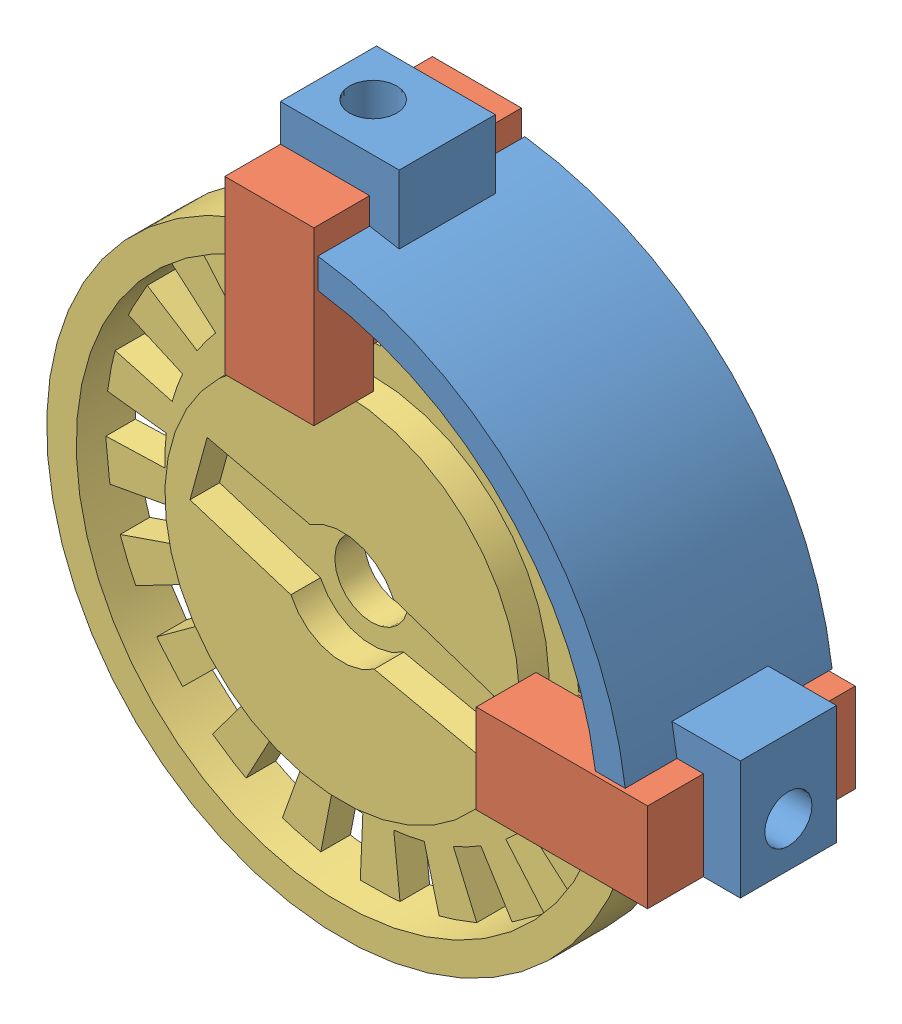
SolidWorks assembly wheel_w_encoder, configuration Default. Lengths in mm.
Overall size (52.67 52.67 14.28).
4 component instances, 3 part files, 9 mates.
Components (placement in the parent):
- encoders_holder2-1: encoders_holder2 [Default] at (1.6965 9.9141 32.1204) size (31.12 31.12 14)
- photo_interrupter-1: photo_interrupter [Default] at (4.7115 29.7141 39.3704) x (0 0 -1) z (-1 0 0) size (14.05 11.6 6.03)
- photo_interrupter-2: photo_interrupter [Default] at (21.4965 12.9291 39.3704) x (0 0 1) z (0 -1 0) size (14.05 11.6 6.03)
- wheel40-1: wheel40 [Default] at (1.6965 9.9141 37.4654) x (0.964469 -0.264196 0) z (0 0 1) size (40 40 4)
Mates (geometry in assembly coordinates):
- Concentric1: concentric: cylinder of encoders_holder2-1 through (1.6965 38.0141 39.3704) axis (0 1 0) radius 1.6; cylinder of photo_interrupter-1 through (1.6965 35.5141 39.3704) axis (0 1 0) radius 1.6
- Coincident1: coincident: plane of encoders_holder2-1 through (4.7215 35.5141 46.6204) normal (0 -1 0); plane of photo_interrupter-1 through (-1.3185 35.5141 46.3954) normal (0 1 0)
- Parallel1: parallel: plane of encoders_holder2-1 through (-1.3285 35.5141 46.6204) normal (-1 0 0); plane of photo_interrupter-1 through (-1.3185 29.7141 39.3704) normal (-1 0 0)
- Concentric2: concentric: cylinder of encoders_holder2-1 through (29.7965 9.9141 39.3704) axis (1 0 0) radius 1.6; cylinder of photo_interrupter-2 through (27.2965 9.9141 39.3704) axis (1 0 0) radius 1.6
- Coincident3: coincident: plane of encoders_holder2-1 through (27.2965 6.8891 46.6204) normal (-1 0 0); plane of photo_interrupter-2 through (27.2965 6.8991 32.3454) normal (1 0 0)
- Parallel2: parallel: plane of encoders_holder2-1 through (27.2965 6.8891 46.6204) normal (0 -1 0); plane of photo_interrupter-2 through (21.4965 6.8991 39.3704) normal (0 -1 0)
- Distance1: distance = 5.6 mm: cylinder of wheel40-1 through (1.6965 9.9141 41.4654) axis (0 0 -1) radius 20; plane of encoders_holder2-1 through (27.2965 6.8891 46.6204) normal (-1 0 0)
- Distance2: distance = 5.6 mm: cylinder of wheel40-1 through (1.6965 9.9141 41.4654) axis (0 0 -1) radius 20; plane of encoders_holder2-1 through (4.7215 35.5141 46.6204) normal (0 -1 0)
- Distance3: distance = 0.88 mm: plane of wheel40-1 through (1.6965 9.9141 41.4654) normal (0 0 1); plane of photo_interrupter-1 through (4.7115 32.7341 42.3454) normal (0 0 -1)
